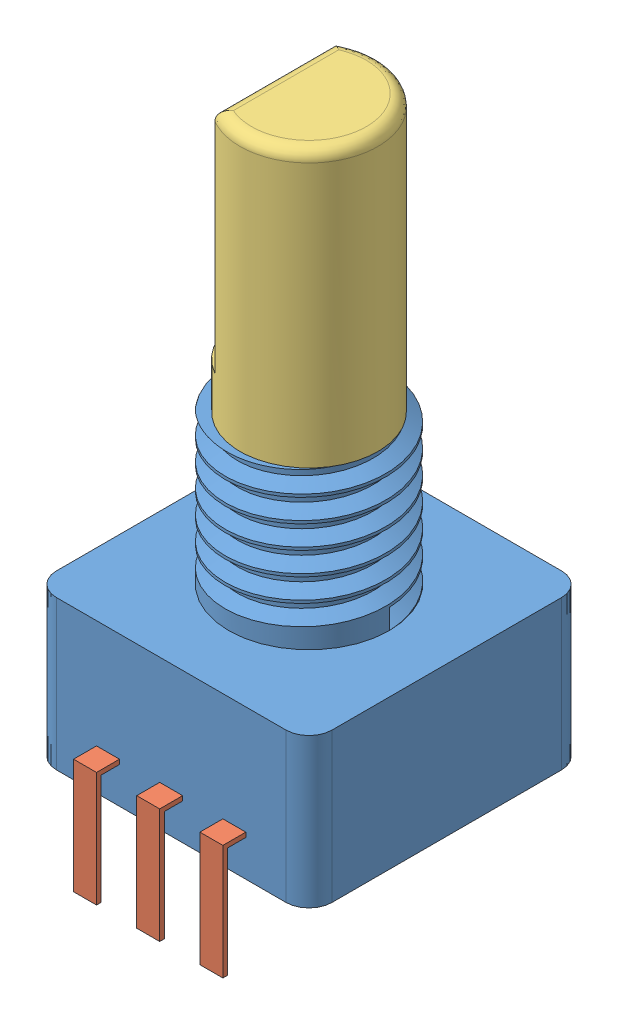
SolidWorks assembly Rotary-Encoder, configuration Default. Lengths in mm.
Overall size (12 28.22 14).
7 component instances, 3 part files, 7 mates.
Components (placement in the parent):
- Rotary-Encoder Base-1: Rotary-Encoder Base [Default] at origin size (12 13.35 12)
- Rotary-Encoder Pin-1: Rotary-Encoder Pin [Default] at (2.75 1.7785 6) x (0 0 -1) z (1 0 0) size (1 5 1)
- Rotary-Encoder Pin-2: Rotary-Encoder Pin [Default] at (0 1.7785 6) x (0 0 -1) z (1 0 0) size (1 5 1)
- Rotary-Encoder Pin-3: Rotary-Encoder Pin [Default] at (-2.75 1.7785 6) x (0 0 -1) z (1 0 0) size (1 5 1)
- Rotary-Encoder Pin-4: Rotary-Encoder Pin [Default] at (-2.75 2.7159 -6) x (0 0 1) z (-1 0 0) size (1 5 1)
- Rotary-Encoder Pin-5: Rotary-Encoder Pin [Default] at (2.75 2.7159 -6) x (0 0 1) z (-1 0 0) size (1 5 1)
- Rotary-Encoder knop-1: Rotary-Encoder knop [Default] at (0 13 0) size (6 12 6)
Mates (geometry in assembly coordinates):
- Coincident1: coincident: plane of Rotary-Encoder Base-1 through (-6 6.5 6) normal (0 0 1); plane of Rotary-Encoder Pin-1 through (3.25 1.5785 6) normal (0 0 -1)
- Distance1: distance = 1.75 mm: plane of Rotary-Encoder Pin-1 through (3.25 1.7785 6) normal (1 0 0); line of Rotary-Encoder Base-1 through (5 0 6) axis (0 1 0)
- Coincident3: coincident: plane of Rotary-Encoder Base-1 through (-6 6.5 -6) normal (0 0 -1); plane of Rotary-Encoder Pin-4 through (-3.25 2.5159 -6) normal (0 0 1)
- Distance2: distance = 1.75 mm: plane of Rotary-Encoder Pin-4 through (-3.25 2.7159 -6) normal (-1 0 0); line of Rotary-Encoder Base-1 through (-5 0 -6) axis (0 1 0)
- Coincident5: coincident: plane of Rotary-Encoder Base-1 through (0 13 0) normal (0 1 0); plane of Rotary-Encoder knop-1 through (0 13 0) normal (0 -1 0)
- Coincident6: coincident: plane of Rotary-Encoder knop-1 through (0 13 0) normal (0 0 1); plane of assembly through (0 0 0) normal (0 0 1)
- Coincident7: coincident: plane of Rotary-Encoder knop-1 through (0 13 0) normal (1 0 0); plane of assembly through (0 0 0) normal (1 0 0)
